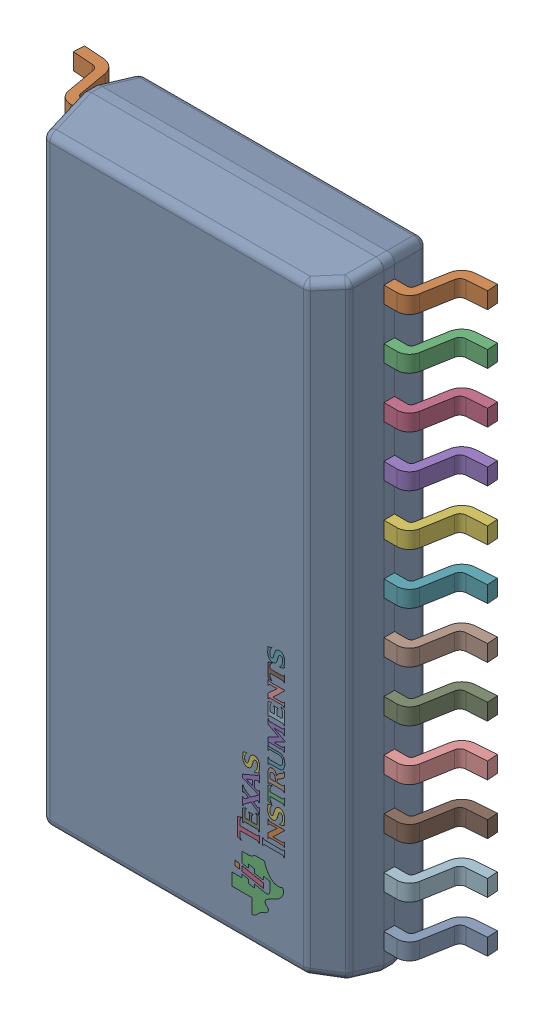
SolidWorks assembly IC_Texas_Instruments_CD74HC4067M96_eec, configuration Défaut. Lengths in mm.
Overall size (10.34 15.4 2.65).
27 component instances, 4 part files, 0 mates.
Components (placement in the parent):
- BODY-SO-1: BODY-SO [Défaut] at (0 0 1.0825) x (0 1 0) z (1 0 0) size (15.4 2.45 7.5)
- LEAD-SO-1: LEAD-SO [Défaut] at (4.315 6.985 0.25) x (0 1 0) z (1 0 0) size (0.41 1.43 1.42)
- LEAD-SO-2: LEAD-SO [Défaut] at (4.315 5.715 0.25) x (0 1 0) z (1 0 0) size (0.41 1.43 1.42)
- LEAD-SO-3: LEAD-SO [Défaut] at (4.315 4.445 0.25) x (0 1 0) z (1 0 0) size (0.41 1.43 1.42)
- LEAD-SO-4: LEAD-SO [Défaut] at (4.315 3.175 0.25) x (0 1 0) z (1 0 0) size (0.41 1.43 1.42)
- LEAD-SO-5: LEAD-SO [Défaut] at (4.315 1.905 0.25) x (0 1 0) z (1 0 0) size (0.41 1.43 1.42)
- LEAD-SO-6: LEAD-SO [Défaut] at (4.315 0.635 0.25) x (0 1 0) z (1 0 0) size (0.41 1.43 1.42)
- LEAD-SO-7: LEAD-SO [Défaut] at (4.315 -0.635 0.25) x (0 1 0) z (1 0 0) size (0.41 1.43 1.42)
- LEAD-SO-8: LEAD-SO [Défaut] at (4.315 -1.905 0.25) x (0 1 0) z (1 0 0) size (0.41 1.43 1.42)
- LEAD-SO-9: LEAD-SO [Défaut] at (4.315 -3.175 0.25) x (0 1 0) z (1 0 0) size (0.41 1.43 1.42)
- LEAD-SO-10: LEAD-SO [Défaut] at (4.315 -4.445 0.25) x (0 1 0) z (1 0 0) size (0.41 1.43 1.42)
- LEAD-SO-11: LEAD-SO [Défaut] at (4.315 -5.715 0.25) x (0 1 0) z (1 0 0) size (0.41 1.43 1.42)
- LEAD-SO-12: LEAD-SO [Défaut] at (4.315 -6.985 0.25) x (0 1 0) z (1 0 0) size (0.41 1.43 1.42)
- LEAD-SO-13: LEAD-SO [Défaut] at (-4.315 6.985 0.25) x (0 -1 0) z (-1 0 0) size (0.41 1.43 1.42)
- LEAD-SO-14: LEAD-SO [Défaut] at (-4.315 5.715 0.25) x (0 -1 0) z (-1 0 0) size (0.41 1.43 1.42)
- LEAD-SO-15: LEAD-SO [Défaut] at (-4.315 4.445 0.25) x (0 -1 0) z (-1 0 0) size (0.41 1.43 1.42)
- LEAD-SO-16: LEAD-SO [Défaut] at (-4.315 3.175 0.25) x (0 -1 0) z (-1 0 0) size (0.41 1.43 1.42)
- LEAD-SO-17: LEAD-SO [Défaut] at (-4.315 1.905 0.25) x (0 -1 0) z (-1 0 0) size (0.41 1.43 1.42)
- LEAD-SO-18: LEAD-SO [Défaut] at (-4.315 0.635 0.25) x (0 -1 0) z (-1 0 0) size (0.41 1.43 1.42)
- LEAD-SO-19: LEAD-SO [Défaut] at (-4.315 -0.635 0.25) x (0 -1 0) z (-1 0 0) size (0.41 1.43 1.42)
- LEAD-SO-20: LEAD-SO [Défaut] at (-4.315 -1.905 0.25) x (0 -1 0) z (-1 0 0) size (0.41 1.43 1.42)
- LEAD-SO-21: LEAD-SO [Défaut] at (-4.315 -3.175 0.25) x (0 -1 0) z (-1 0 0) size (0.41 1.43 1.42)
- LEAD-SO-22: LEAD-SO [Défaut] at (-4.315 -4.445 0.25) x (0 -1 0) z (-1 0 0) size (0.41 1.43 1.42)
- LEAD-SO-23: LEAD-SO [Défaut] at (-4.315 -5.715 0.25) x (0 -1 0) z (-1 0 0) size (0.41 1.43 1.42)
- LEAD-SO-24: LEAD-SO [Défaut] at (-4.315 -6.985 0.25) x (0 -1 0) z (-1 0 0) size (0.41 1.43 1.42)
- Texas Logo Yury-1: Texas Logo Yury [Défaut] at (2.174 -7.1221 2.551) x (0 1 0) z (0 0 1) size (1.32 1.29 0.11)
- Texas Logo Yury - Copy-1: Texas Logo Yury - Copy [Défaut] at (2.0641 -7.1534 2.551) x (0 1 0) z (0 0 1) size (4.61 1.2 0.1)
